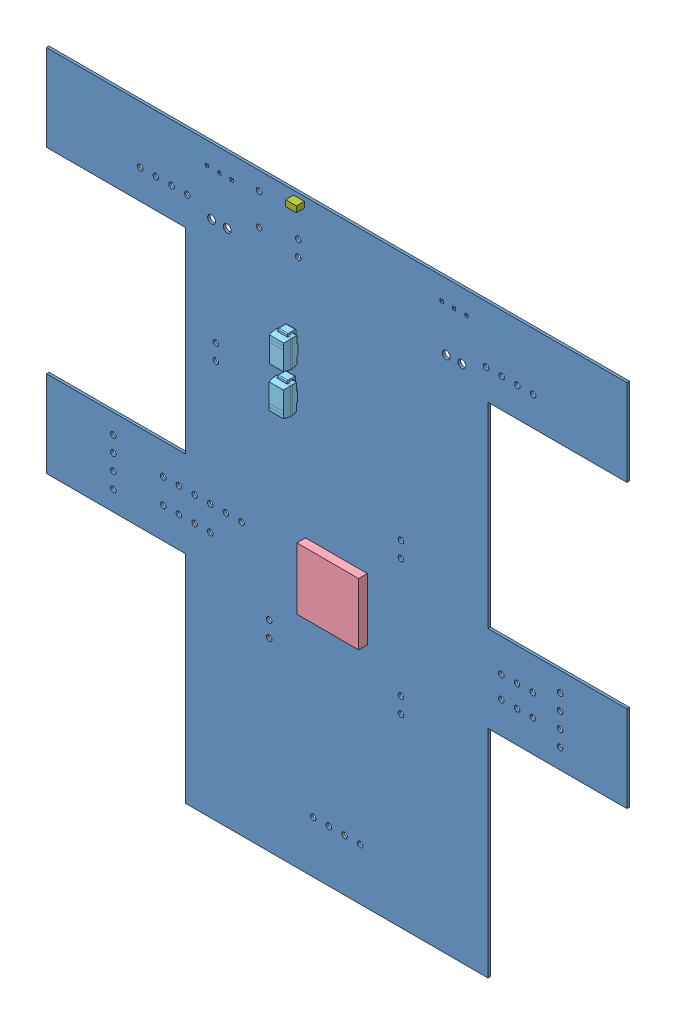
SolidWorks assembly sumobot, configuration Default. Lengths in mm.
Overall size (94 94.75 4.44).
18 component instances, 7 part files, 0 mates.
Components (placement in the parent):
- Board-1: Board [Default] at (0 0 -0.4115) size (94 94.75 0.41)
- U5-1: U5 [Default] at origin size (8.3 5.6 1.55)
  - 575414720-1: 575414720 [Default] at (46.736 21.066 -2.0115) size (8.3 5.6 1.55)
    - Extruded-1: Extruded [Default] at origin size (8.3 5.6 1.55)
- U4-1: U4 [Default] at origin size (8.3 5.6 1.55)
  - 703633856-1: 703633856 [Default] at (46.99 61.452 -2.0115) size (8.3 5.6 1.55)
    - Extruded_2-1: Extruded_2 [Default] at origin size (8.3 5.6 1.55)
- U1-1: U1 [Default] at origin size (10 10 1.4)
  - 642238864-1: 642238864 [Default] at (47 42 0.05) size (10 10 1.4)
    - Extruded_3-1: Extruded_3 [Default] at origin size (10 10 1.4)
- D4-1: D4 [Default] at origin size (2.6 5.21 2.43)
  - SW3dPS-DO-214AC_SMA-1: SW3dPS-DO-214AC_SMA [Default] at (39.5986 66.278 1.4) x (-1 0 0) z (0 0 1) size (2.6 5.21 2.43)
- D3-1: D3 [Default] at origin size (2.6 5.21 2.43)
  - SW3dPS-DO-214AC_SMA-1: SW3dPS-DO-214AC_SMA [Default] at (39.6494 72.882 1.4) x (1 0 0) z (0 0 1) size (2.6 5.21 2.43)
- D2-1: D2 [Default] at origin size (1.75 0.95 1.7)
  - User_Library-0603_SMD_Capacitor-1: User_Library-0603_SMD_Capacitor [Default] at (40.9068 93.71 0) x (-1 0 0) z (0 0 1) size (1.6 0.31 0.8)
  - 642239760-1: 642239760 [Default] at (40.894 93.583 0) size (1.75 0.95 1.3)
    - Extruded_4-1: Extruded_4 [Default] at origin size (1.75 0.95 1.3)
